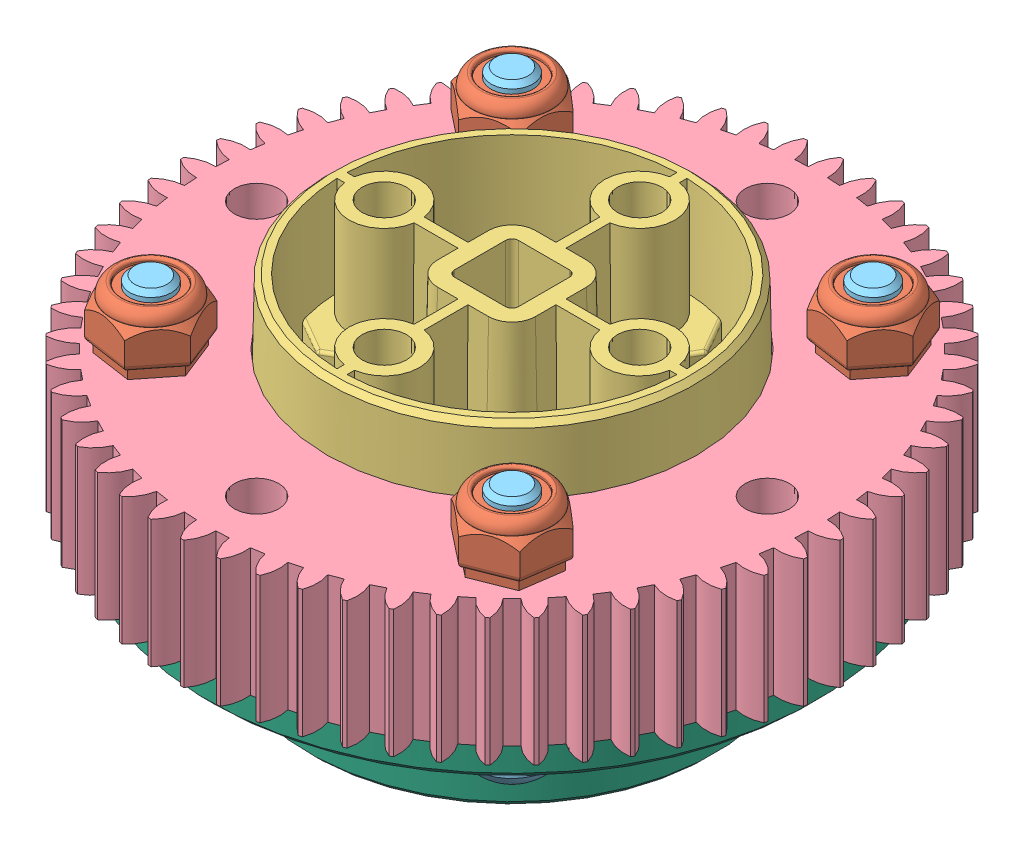
SolidWorks assembly 276-1810-SMALL, configuration Default. Lengths in mm.
Overall size (65.62 31.88 65.62).
13 component instances, 6 part files, 0 mates.
Components (placement in the parent):
- ASM0001_ASM-1: ASM0001_ASM [Default] at origin size (65.62 31.88 65.62)
  - 276-1810-009_ANY-1: 276-1810-009_ANY [Default] at (2.7414 -9.6953 -1.5035) x (0 0 -1) z (1 0 0) size (57.7 8.89 57.7)
  - NUT-832-NYLOCK_ANY_1-1: NUT-832-NYLOCK_ANY_1 [Default] at (-15.2191 3.961 -19.464) x (0.929251 0 -0.369448) z (0.369448 0 0.929251) size (10.2 5.86 8.12)
  - 276-1810-008_ANY-1: 276-1810-008_ANY [Default] at (2.7414 0.0837 -1.5035) size (43.92 18.8 43.92)
  - 276-1810-006_ANY-1: 276-1810-006_ANY [Default] at (2.7414 3.0047 -1.5035) x (0 0 1) z (1 0 0) size (65.62 12.7 65.62)
  - NUT-832-NYLOCK_ANY_1-2: NUT-832-NYLOCK_ANY_1 [Default] at (-15.2191 3.961 16.457) x (-0.369448 0 -0.929251) z (0.929251 0 -0.369448) size (10.2 5.86 8.12)
  - SCREW-832-0875_ANY-1: SCREW-832-0875_ANY [Default] at (-15.2191 -15.0801 -19.464) x (0 1 0) z (-1 0 0) size (24.43 7.92 7.92)
  - SCREW-832-0875_ANY-2: SCREW-832-0875_ANY [Default] at (-15.2191 -15.0801 16.457) x (0 1 0) z (0 0 1) size (24.43 7.92 7.92)
  - NUT-832-NYLOCK_ANY_1-3: NUT-832-NYLOCK_ANY_1 [Default] at (20.7019 3.961 16.457) x (-0.929251 0 0.369448) z (-0.369448 0 -0.929251) size (10.2 5.86 8.12)
  - SCREW-832-0875_ANY-3: SCREW-832-0875_ANY [Default] at (20.7019 -15.0801 -19.464) x (0 1 0) z (0 0 -1) size (24.43 7.92 7.92)
  - SCREW-832-0875_ANY-4: SCREW-832-0875_ANY [Default] at (20.7019 -15.0801 16.457) x (0 1 0) z (1 0 0) size (24.43 7.92 7.92)
  - 276-1810-007_ANY-1: 276-1810-007_ANY [Default] at (2.7414 -12.8703 -1.5035) x (0 0 1) z (1 0 0) size (60.45 12.7 60.45)
  - NUT-832-NYLOCK_ANY_1-4: NUT-832-NYLOCK_ANY_1 [Default] at (20.7019 3.961 -19.464) x (0.369448 0 0.929251) z (-0.929251 0 0.369448) size (10.2 5.86 8.12)
